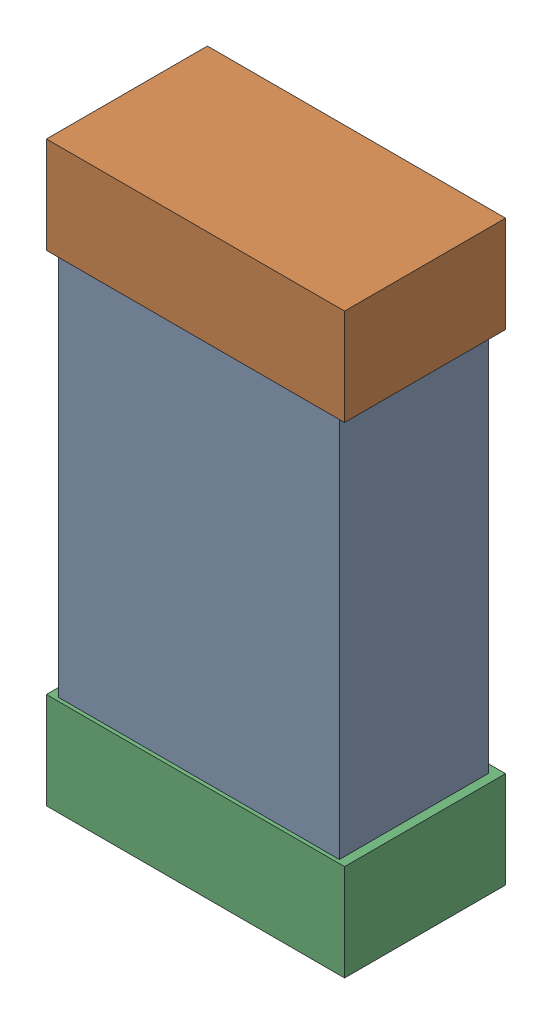
SolidWorks assembly R6, configuration Default. Lengths in mm.
Overall size (0.85 1.65 0.46).
6 component instances, 2 part files, 0 mates.
Components (placement in the parent):
- 432124816_45-1: 432124816_45 [Default] at (27.9959 22.0611 0.025) size (0.8 1.5 0.42)
  - Extruded (1)-1: Extruded (1) [Default] at origin size (0.8 1.5 0.42)
- 432138512_90-1: 432138512_90 [Default] at (27.9959 22.747 0.001) size (0.85 0.28 0.46)
  - Extruded-1: Extruded [Default] at origin size (0.85 0.28 0.46)
- 432138512_91-1: 432138512_91 [Default] at (27.9959 21.3754 0.001) size (0.85 0.28 0.46)
  - Extruded-1: Extruded [Default] at origin size (0.85 0.28 0.46)
